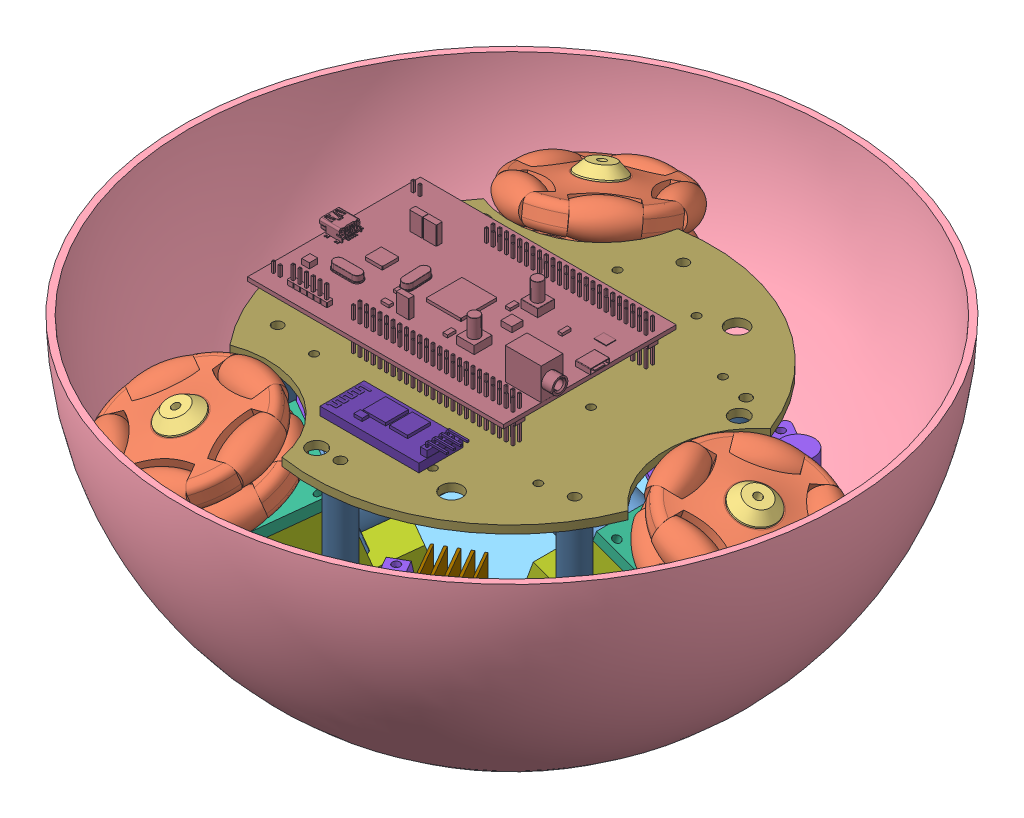
SolidWorks assembly _omniwheel_robot_17_v2, configuration Default. Lengths in mm.
Overall size (245 245 237.86).
49 component instances, 17 part files, 50 mates.
Components (placement in the parent):
- omniwheel_steeldrive-1: omniwheel_steeldrive [Default] at (64.8481 -38.8452 0) x (0.34202 0.939693 0) z (-0.939693 0.34202 0) size (63.8 58 98.7)
  - motor_and_drive-1: motor_and_drive [Default] at origin size (41.8 32 84.7)
  - omniwheel_shaftless-1: omniwheel_shaftless [Default] at (44.25 0 -8) size (27.1 58 58)
  - omniwheel_adapter-1: omniwheel_adapter [Default] at (27.3 0 0) x (0 0 -1) z (1 0 0) size (16.2 16.2 34)
- omniwheel_steeldrive-2: omniwheel_steeldrive [Default] at (-32.424 -38.8452 -56.1601) x (-0.17101 0.939693 -0.296198) z (0.469846 0.34202 0.813798) size (63.8 58 98.7)
  - motor_and_drive-1: motor_and_drive [Default] at origin size (41.8 32 84.7)
  - omniwheel_shaftless-1: omniwheel_shaftless [Default] at (44.25 0 -8) size (27.1 58 58)
  - omniwheel_adapter-1: omniwheel_adapter [Default] at (27.3 0 0) x (0 0 -1) z (1 0 0) size (16.2 16.2 34)
- omniwheel_steeldrive-3: omniwheel_steeldrive [Default] at (-32.424 -38.8452 56.1601) x (-0.17101 0.939693 0.296198) z (0.469846 0.34202 -0.813798) size (63.8 58 98.7)
  - motor_and_drive-1: motor_and_drive [Default] at origin size (41.8 32 84.7)
  - omniwheel_shaftless-1: omniwheel_shaftless [Default] at (44.25 0 -8) size (27.1 58 58)
  - omniwheel_adapter-1: omniwheel_adapter [Default] at (27.3 0 0) x (0 0 -1) z (1 0 0) size (16.2 16.2 34)
- ball-2: ball [Default] at (0 31.9745 0) size (249.92 121.81 249.92) (hidden)
- round_baseplate-1: round_baseplate [Default] at (0 -44.3601 0) x (1 0 0) z (0 -1 0) size (164.52 167.6 5)
- motor_plate-1: motor_plate [Default] at (-36.6993 -15.3529 -63.565) x (-0.469846 -0.34202 -0.813798) z (-0.17101 0.939693 -0.296198) size (44 44 4)
- motor_adapter-1: motor_adapter [Default] at (-18.5676 -38.8452 -64.1601) x (0.17101 -0.939693 0.296198) z (0.866025 0 -0.5) size (41.14 55.5 44)
- motor_adapter-2: motor_adapter [Default] at (-46.2804 -38.8452 48.1601) x (0.17101 -0.939693 -0.296198) z (-0.866025 0 -0.5) size (41.14 55.5 44)
- motor_adapter-3: motor_adapter [Default] at (64.8481 -38.8452 16) x (-0.34202 -0.939693 0) z (0 0 1) size (41.14 55.5 44)
- motor_plate-2: motor_plate [Default] at (-36.6993 -15.3529 63.565) x (-0.469846 -0.34202 0.813798) z (-0.17101 0.939693 0.296198) size (44 44 4)
- motor_plate-3: motor_plate [Default] at (73.3986 -15.3529 0) x (0.939693 -0.34202 0) z (0.34202 0.939693 0) size (44 44 4)
- ibt-3_assembly-2: ibt-3_assembly [Default] at (-62.0816 -39.3601 0) x (-1 0 0) z (0 0 -1) size (43.5 20 48.5)
  - Part12^ibt-3_assembly-1: Part12^ibt-3_assembly [Default] at origin size (43.5 17 48.5) (virtual)
  - Part13^ibt-3_assembly-1: Part13^ibt-3_assembly [Default] at (0 2 0) x (1 0 0) z (0 1 0) size (24 16 18) (virtual)
- ibt-3_assembly-3: ibt-3_assembly [Default] at (31.0408 -39.3601 53.7643) x (0.5 0 0.866025) z (-0.866025 0 0.5) size (43.5 20 48.5)
  - Part12^ibt-3_assembly-1: Part12^ibt-3_assembly [Default] at origin size (43.5 17 48.5) (virtual)
  - Part13^ibt-3_assembly-1: Part13^ibt-3_assembly [Default] at (0 2 0) x (1 0 0) z (0 1 0) size (24 16 18) (virtual)
- ibt-3_assembly-4: ibt-3_assembly [Default] at (31.0408 -39.3601 -53.7643) x (0.5 0 -0.866025) z (0.866025 0 0.5) size (43.5 20 48.5)
  - Part12^ibt-3_assembly-1: Part12^ibt-3_assembly [Default] at origin size (43.5 17 48.5) (virtual)
  - Part13^ibt-3_assembly-1: Part13^ibt-3_assembly [Default] at (0 2 0) x (1 0 0) z (0 1 0) size (24 16 18) (virtual)
- Column-1: Column [Default] at (0 -44.3601 0) x (-1 0 0) z (0 1 0) size (10 10 55)
- Column-2: Column [Default] at (0 -44.3601 0) x (-0.5 0 0.866025) z (0 1 0) size (10 10 55)
- Column-3: Column [Default] at (0 -44.3601 0) x (0.5 0 0.866025) z (0 1 0) size (10 10 55)
- Column-4: Column [Default] at (0 -44.3601 0) x (1 0 0) z (0 1 0) size (10 10 55)
- Column-5: Column [Default] at (0 -44.3601 0) x (0.5 0 -0.866025) z (0 1 0) size (10 10 55)
- Column-6: Column [Default] at (0 -44.3601 0) x (-0.5 0 -0.866025) z (0 1 0) size (10 10 55)
- battery-1: battery [Default] at (0 -58.8601 0) size (95 19 70)
- upper_baseplate-1: upper_baseplate [Default] at (0 10.6399 0) x (-0.5 0 -0.866025) z (0 1 0) size (147.01 151.96 3)
- stm32f4-1: stm32f4 [Default] at (30.6 23.6399 -31.7) x (-1 0 0) z (0 0 -1) size (102.57 23 65.5)
- angle_spacer-1: angle_spacer [Default] at (0 -49.3601 0) x (1 0 0) z (0 -1 0) size (8 46 5)
- angle_spacer-2: angle_spacer [Default] at (0 -49.3601 0) x (-0.5 0 -0.866025) z (0 -1 0) size (8 46 5)
- angle_spacer-3: angle_spacer [Default] at (0 -49.3601 0) x (-0.5 0 0.866025) z (0 -1 0) size (8 46 5)
- angle_spacer-4: angle_spacer [Default] at (-27 -49.3601 0) x (1 0 0) z (0 -1 0) size (8 46 5)
- angle_spacer_2-1: angle_spacer_2 [Default] at (13.5305 -49.3601 -23.4354) x (-0.5 0 0.866025) z (0 -1 0) size (8 46 5)
- angle_spacer_2-2: angle_spacer_2 [Default] at (13.5305 -49.3601 23.4354) x (-0.5 0 -0.866025) z (0 -1 0) size (8 46 5)
- small_spacer^_omniwheel_robot_17_v2-1: small_spacer^_omniwheel_robot_17_v2 [Default] at (0 -44.3601 0) x (-1 0 0) z (0 1 0) size (42.64 28 5) (virtual)
- small_spacer^_omniwheel_robot_17_v2-2: small_spacer^_omniwheel_robot_17_v2 [Default] at (0 -44.3601 0) x (0.5 0 0.866025) z (0 1 0) size (42.64 28 5) (virtual)
- small_spacer^_omniwheel_robot_17_v2-3: small_spacer^_omniwheel_robot_17_v2 [Default] at (0 -44.3601 0) x (0.5 0 -0.866025) z (0 1 0) size (42.64 28 5) (virtual)
- HC-06-1: HC-06 [Default] at (4.1359 17.5399 49.7821) size (43.9 7.8 16.7) (hidden)
- battery-2: battery [Default] at (0 -77.8601 0) size (95 19 70) (suppressed, hidden)
Mates (geometry in assembly coordinates):
- Coincident1: coincident: point of omniwheel_steeldrive-1/motor_and_drive-1
- Parallel1: parallel: line of ? through (16.264 -18.7067 -13.5) axis (0 0 1)
- Coincident4: coincident: line of omniwheel_steeldrive-1/motor_and_drive-1 through (87.5 0 0) axis (-0.34202 -0.939693 0)
- Angle1: planar angle = 1.570796 rad aligned: plane of omniwheel_steeldrive-1/motor_and_drive-1 through (64.8481 -38.8452 0) normal (-0.939693 0.34202 0); plane of assembly through (0 0 0) normal (0 0 1)
- Angle3: planar angle = 1.22173 rad anti-aligned: line of omniwheel_steeldrive-1/motor_and_drive-1 through (87.5 0 0) axis (-0.34202 -0.939693 0)
- Coincident7: coincident aligned: plane of ball-2 through (0 31.9745 0) normal (0 0 1); plane of assembly through (0 0 0) normal (0 0 1)
- Coincident8: coincident aligned: plane of ball-2 through (0 31.9745 0) normal (1 0 0); plane of assembly through (0 0 0) normal (1 0 0)
- Parallel4: parallel anti-aligned: plane of round_baseplate-1 through (0 -49.3601 0) normal (0 -1 0); plane of assembly through (0 0 0) normal (0 1 0)
- Coincident10: coincident aligned: plane of round_baseplate-1 through (0 -44.3601 0) normal (0 0 1); plane of assembly through (0 0 0) normal (0 0 1)
- Coincident11: coincident aligned: plane of round_baseplate-1 through (0 -44.3601 0) normal (1 0 0); plane of assembly through (0 0 0) normal (1 0 0)
- Tangent1: tangent: plane of omniwheel_steeldrive-3/motor_and_drive-1 through (-32.424 -38.8452 56.1601) normal (0.17101 -0.939693 -0.296198); circle of round_baseplate-1
- InPlace1: in place: plane of omniwheel_steeldrive-2/motor_and_drive-1 through (-36.8924 -21.1673 -81.8996) normal (-0.17101 0.939693 -0.296198); plane of ? through (-1.8258 10.0329 -3.1624) normal (-0.17101 0.939693 -0.296198); moOrthogonalPlaneRef_w of omniwheel_steeldrive-2/motor_and_drive-1 through (-36.8924 -21.1673 -81.8996) normal (-0.17101 0.939693 -0.296198); unknown of ?; plane of omniwheel_steeldrive-2/motor_and_drive-1 through (-36.8924 -21.1673 -81.8996) normal (-0.17101 0.939693 -0.296198); unknown of ?; plane of omniwheel_steeldrive-2/motor_and_drive-1 through (-36.8924 -21.1673 -81.8996) normal (-0.17101 0.939693 -0.296198); unknown of motor_plate-1
- Coincident13: coincident aligned: plane of omniwheel_steeldrive-2/motor_and_drive-1; plane of motor_plate-1
- Coincident14: coincident aligned: moOrthogonalPlaneRef_w of omniwheel_steeldrive-2/motor_and_drive-1 through (-36.6993 -15.3529 -63.565) normal (-0.866025 0 0.5); plane of motor_plate-1 through (-36.6993 -15.3529 -63.565) normal (-0.866025 0 0.5)
- Coincident15: coincident anti-aligned: moOrthogonalPlaneRef_w of omniwheel_steeldrive-2/motor_and_drive-1 through (-36.6993 -15.3529 -63.565) normal (0.469846 0.34202 0.813798); plane of motor_plate-1 through (-36.6993 -15.3529 -63.565) normal (-0.469846 -0.34202 -0.813798)
- InPlace3: in place: plane of omniwheel_steeldrive-2/motor_and_drive-1 through (-11.6944 -9.3658 -52.2553) normal (0.866025 0 -0.5); plane of ? through (13.8564 0 -8) normal (0.866025 0 -0.5); plane of omniwheel_steeldrive-2/motor_and_drive-1 through (-11.6944 -9.3658 -52.2553) normal (0.866025 0 -0.5); unknown of ?; plane of omniwheel_steeldrive-2/motor_and_drive-1 through (-11.6944 -9.3658 -52.2553) normal (0.866025 0 -0.5); plane of ? through (13.8564 0 -8) normal (-0.5 0 -0.866025); plane of omniwheel_steeldrive-2/motor_and_drive-1 through (-11.6944 -9.3658 -52.2553) normal (0.866025 0 -0.5); unknown of motor_adapter-1
- Coincident19: coincident aligned: plane of omniwheel_steeldrive-2/motor_and_drive-1; plane of motor_adapter-1
- Coincident20: coincident aligned: moOrthogonalPlaneRef_w of omniwheel_steeldrive-2/motor_and_drive-1 through (-18.5676 -38.8452 -64.1601) normal (-0.469846 -0.34202 -0.813798); plane of motor_adapter-1 through (-18.5676 -38.8452 -64.1601) normal (-0.469846 -0.34202 -0.813798)
- Coincident21: coincident anti-aligned: moOrthogonalPlaneRef_w of omniwheel_steeldrive-2/motor_and_drive-1 through (-18.5676 -38.8452 -64.1601) normal (-0.17101 0.939693 -0.296198); plane of motor_adapter-1 through (-18.5676 -38.8452 -64.1601) normal (0.17101 -0.939693 0.296198)
- Distance2: distance = 5 mm anti-aligned: plane of round_baseplate-1 through (0 -44.3601 0) normal (0 1 0); plane of ibt-3_assembly-2/Part12^ibt-3_assembly-1 through (-62.0816 -39.3601 0) normal (0 -1 0)
- Coincident24: coincident anti-aligned: plane of ibt-3_assembly-2/Part12^ibt-3_assembly-1 through (-62.0816 -39.3601 0) normal (0 0 -1); plane of assembly through (0 0 0) normal (0 0 1)
- Distance1: distance = 9 mm: point of motor_adapter-2; plane of ibt-3_assembly-2/Part12^ibt-3_assembly-1 through (-40.3316 -37.3601 -24.25) normal (1 0 0)
- InPlace4: in place: plane of round_baseplate-1 through (0 -44.3601 0) normal (0 1 0); plane of Column-4 through (0 -44.3601 0) normal (0 1 0); plane of round_baseplate-1 through (0 -44.3601 0) normal (0 1 0); plane of Column-4 through (0 -44.3601 0) normal (0 0 -1); plane of round_baseplate-1 through (0 -44.3601 0) normal (0 1 0); line of Column-4 through (-55 0 -44.3601) axis (0 1 0); plane of round_baseplate-1 through (0 -44.3601 0) normal (0 1 0); unknown of ?
- Coincident27: coincident aligned: plane of round_baseplate-1; plane of Column-1
- Coincident28: coincident aligned: moOrthogonalPlaneRef_w of round_baseplate-1 through (0 -44.3601 0) normal (0 0 1); plane of Column-1 through (0 -44.3601 0) normal (0 0 1)
- Coincident29: coincident anti-aligned: moOrthogonalPlaneRef_w of round_baseplate-1 through (0 -44.3601 0) normal (1 0 0); plane of Column-1 through (0 -44.3601 0) normal (-1 0 0)
- Coincident30: coincident: point of battery-1; line of assembly
- Parallel5: parallel aligned: plane of battery-1 through (0 -58.8601 0) normal (0 1 0); plane of assembly through (0 0 0) normal (0 1 0)
- Coincident32: coincident aligned: plane of battery-1 through (0 -58.8601 0) normal (1 0 0); plane of assembly through (0 0 0) normal (1 0 0)
- Tangent3: tangent anti-aligned: plane of round_baseplate-1 through (0 -49.3601 0) normal (0 -1 0); cylinder of battery-1 through (0 -58.8601 -35) axis (0 0 1) radius 9.5
- InPlace5: in place: plane of Column-6 through (56.2917 15.6399 -32.5) normal (0 1 0); plane of ? through (0 15.6399 0) normal (0 1 0); plane of Column-6 through (56.2917 15.6399 -32.5) normal (0 1 0); plane of ? through (0 15.6399 0) normal (0 0 -1); plane of Column-6 through (56.2917 15.6399 -32.5) normal (0 1 0); line of ? through (-55 0 15.6399) axis (0 1 0); plane of Column-6 through (56.2917 10.6399 -32.5) normal (0 1 0); unknown of upper_baseplate-1
- Coincident33: coincident aligned: plane of Column-6; plane of upper_baseplate-1
- Coincident34: coincident aligned: moOrthogonalPlaneRef_w of Column-6 through (0 10.6399 0) normal (-0.866025 0 0.5); plane of upper_baseplate-1 through (0 10.6399 0) normal (-0.866025 0 0.5)
- Coincident35: coincident anti-aligned: moOrthogonalPlaneRef_w of Column-6 through (0 10.6399 0) normal (0.5 0 0.866025); plane of upper_baseplate-1 through (0 10.6399 0) normal (-0.5 0 -0.866025)
- Parallel6: parallel aligned: plane of stm32f4-1 through (30.6 23.6399 -31.7) normal (0 1 0); plane of assembly through (0 0 0) normal (0 1 0)
- Distance3: distance = 10 mm anti-aligned: plane of stm32f4-1 through (30.6 23.6399 -31.7) normal (0 -1 0); plane of upper_baseplate-1 through (0 13.6399 0) normal (0 1 0)
- InPlace6: in place: plane of round_baseplate-1 through (0 -49.3601 0) normal (0 -1 0); plane of ? through (0 -49.3601 0) normal (0 -1 0); plane of round_baseplate-1 through (0 -49.3601 0) normal (0 -1 0); unknown of ?; plane of round_baseplate-1 through (0 -49.3601 0) normal (0 -1 0); line of ? through (-55 0 -49.3601) axis (0 -1 0); plane of round_baseplate-1 through (0 -49.3601 0) normal (0 -1 0); unknown of angle_spacer-1
- Coincident39: coincident aligned: plane of round_baseplate-1; plane of angle_spacer-1
- Coincident40: coincident aligned: moOrthogonalPlaneRef_w of round_baseplate-1 through (0 -49.3601 0) normal (0 0 1); plane of angle_spacer-1 through (0 -49.3601 0) normal (0 0 1)
- Coincident41: coincident anti-aligned: moOrthogonalPlaneRef_w of round_baseplate-1 through (0 -49.3601 0) normal (-1 0 0); plane of angle_spacer-1 through (0 -49.3601 0) normal (1 0 0)
- Coincident42: coincident anti-aligned: plane of round_baseplate-1 through (0 -49.3601 0) normal (0 -1 0); plane of angle_spacer_2-1 through (-37.1213 -49.3601 26.296) normal (0 1 0)
- Parallel8: parallel aligned: plane of angle_spacer-3 through (-52.6518 -54.3601 53.1956) normal (-0.5 0 0.866025); plane of angle_spacer_2-1 through (-39.1213 -54.3601 29.7601) normal (-0.5 0 0.866025)
- Perpendicular1: perpendicular: plane of angle_spacer-3 through (-48.6518 -54.3601 46.2674) normal (0.5 0 -0.866025); plane of angle_spacer_2-1 through (13.5305 -49.3601 -23.4354) normal (-0.866025 0 -0.5)
- Tangent4: tangent: curve of round_baseplate-1; curve of angle_spacer_2-1
- Parallel10: parallel anti-aligned: plane of stm32f4-1 through (30.6 23.6399 -31.7) normal (0 0 -1); plane of assembly through (0 0 0) normal (0 0 1)
- InPlace7: in place: plane of round_baseplate-1 through (0 -44.3601 0) normal (0 1 0); plane of Column-4 through (0 -44.3601 0) normal (0 1 0); plane of round_baseplate-1 through (0 -44.3601 0) normal (0 1 0); plane of Column-4 through (0 -44.3601 0) normal (0 0 -1); plane of round_baseplate-1 through (0 -44.3601 0) normal (0 1 0); line of Column-4 through (-55 0 -44.3601) axis (0 1 0); plane of round_baseplate-1 through (0 -44.3601 0) normal (0 1 0); unknown of ?
- Coincident43: coincident aligned: plane of round_baseplate-1; plane of small_spacer^_omniwheel_robot_17_v2-1
- Coincident44: coincident aligned: moOrthogonalPlaneRef_w of round_baseplate-1 through (0 -44.3601 0) normal (0 0 1); plane of small_spacer^_omniwheel_robot_17_v2-1 through (0 -44.3601 0) normal (0 0 1)
- Coincident45: coincident anti-aligned: moOrthogonalPlaneRef_w of round_baseplate-1 through (0 -44.3601 0) normal (1 0 0); plane of small_spacer^_omniwheel_robot_17_v2-1 through (0 -44.3601 0) normal (-1 0 0)
- Coincident43: coincident: point of stm32f4-1; line of assembly
